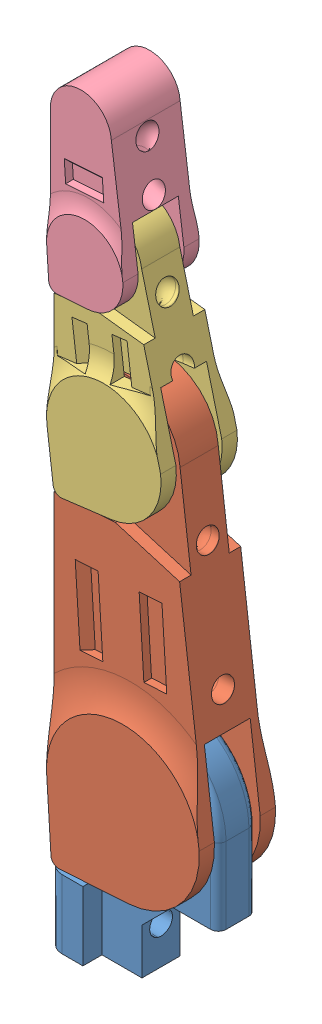
SolidWorks assembly rh1f1 v4, configuration Default. Lengths in mm.
Overall size (25.45 99.09 12).
4 component instances, 4 part files, 9 mates.
Components (placement in the parent):
- robot hand v4 f1 4-1: robot hand v4 f1 4 [Default] at (7.4493 16.7233 27.6774) x (0 1 0) z (0 0 1) size (30 20 10)
- rhf1l1-1: rhf1l1 [Default] at (6.1993 36.6842 27.6774) x (-0.0625 0.998045 0) z (0 0 1) size (57.5 21.9 12)
- rhf1l2-1: rhf1l2 [Default] at (3.6993 66.5667 27.6774) x (-0.125 0.992157 0) z (0 0 1) size (32.5 16.23 12)
- rhf1l3-1: rhf1l3 [Default] at (1.9493 83.9715 27.6774) x (-0.066667 0.997775 0) z (0 0 1) size (24 10.94 11)
Mates (geometry in assembly coordinates):
- Concentric1: concentric aligned: cylinder of robot hand v4 f1 4-1 through (7.4493 16.7233 30.1774) axis (0 0 -1) radius 3; cylinder of rhf1l1-1 through (7.4493 16.7233 32.6774) axis (0 0 -1) radius 2.5
- Concentric2: concentric aligned: cylinder of rhf1l1-1 through (4.9493 56.6451 32.1774) axis (0 0 -1) radius 3; cylinder of rhf1l2-1 through (4.9493 56.6451 32.6774) axis (0 0 -1) radius 2.5
- Concentric3: concentric aligned: cylinder of rhf1l2-1 through (2.4493 76.4882 32.1774) axis (0 0 -1) radius 3; cylinder of rhf1l3-1 through (2.4493 76.4882 32.6774) axis (0 0 -1) radius 2.5
- Width4: width: plane of robot hand v4 f1 4-1 through (7.4493 16.7233 30.1774) normal (0 0 1); plane of rhf1l1-1 through (7.4493 16.7233 25.1774) normal (0 0 -1); plane of robot hand v4 f1 4-1 through (6.1993 36.6842 30.6774) normal (0 0 -1); plane of rhf1l1-1 through (6.1993 36.6842 24.6774) normal (0 0 1)
- Width6: width: plane of rhf1l2-1 through (3.6993 66.5667 30.1774) normal (0 0 1); plane of rhf1l3-1 through (3.6993 66.5667 25.1774) normal (0 0 -1); plane of rhf1l2-1 through (1.9493 83.9715 24.6774) normal (0 0 1); plane of rhf1l3-1 through (1.9493 83.9715 30.6774) normal (0 0 -1)
- Coincident1: coincident aligned: plane of rhf1l2-1 through (-2.5507 66.5667 31.6774) normal (-1 0 0); plane of rhf1l1-1 through (-2.5507 36.6842 31.6774) normal (-1 0 0)
- Coincident2: coincident aligned: plane of robot hand v4 f1 4-1 through (-2.5507 16.7233 30.1774) normal (-1 0 0); plane of rhf1l1-1 through (-2.5507 36.6842 31.6774) normal (-1 0 0)
- Coincident3: coincident aligned: plane of rhf1l2-1 through (-2.5507 66.5667 31.6774) normal (-1 0 0); plane of rhf1l3-1 through (-2.5507 83.9715 29.6774) normal (-1 0 0)
- Width7: width: plane of rhf1l1-1 through (6.1993 36.6842 30.1774) normal (0 0 1); plane of rhf1l1-1 through (6.1993 36.6842 25.1774) normal (0 0 -1); plane of rhf1l2-1 through (3.6993 66.5667 30.6774) normal (0 0 -1); plane of rhf1l2-1 through (3.6993 66.5667 24.6774) normal (0 0 1)
